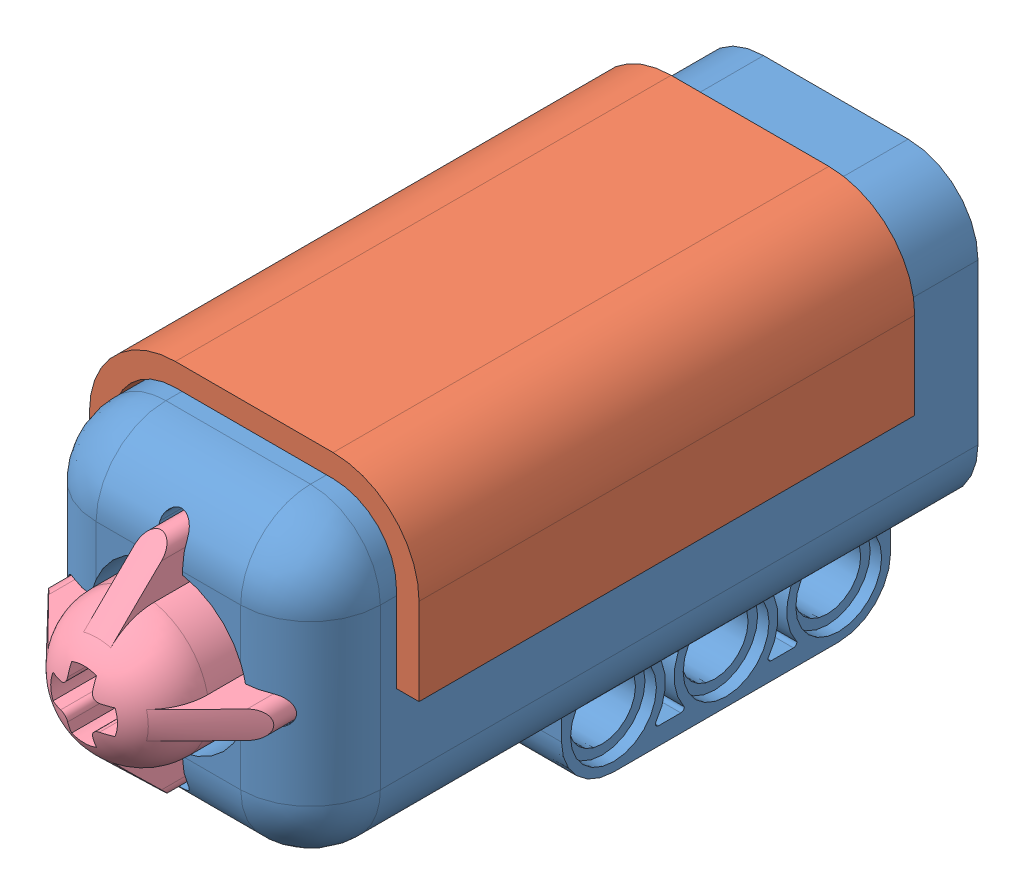
SolidWorks assembly Sensor Touch, configuration Default. Lengths in mm.
Overall size (24.05 31.58 54.37).
4 component instances, 4 part files, 0 mates.
Components (placement in the parent):
- Sensor Touch Body-1: Sensor Touch Body [Default] x (-1 0 0) z (0 -1 0) size (22.43 50.04 29.96)
- Sensor Touch Cover-1: Sensor Touch Cover [Default] at (0 -0.0225 17.75) x (-1 0 0) z (0 0 -1) size (23.6 12.37 35.5)
- NXT Socket-1: NXT Socket [Default] at (0 -1.35 -23.9) x (-1 0 0) z (0 0 1) size (12.5 15 12.59)
- Sensor Touch Button-1: Sensor Touch Button [Default] at (0 0 20.4) x (-1 0 0) z (0 1 0) size (16.15 9.9 16.15)
